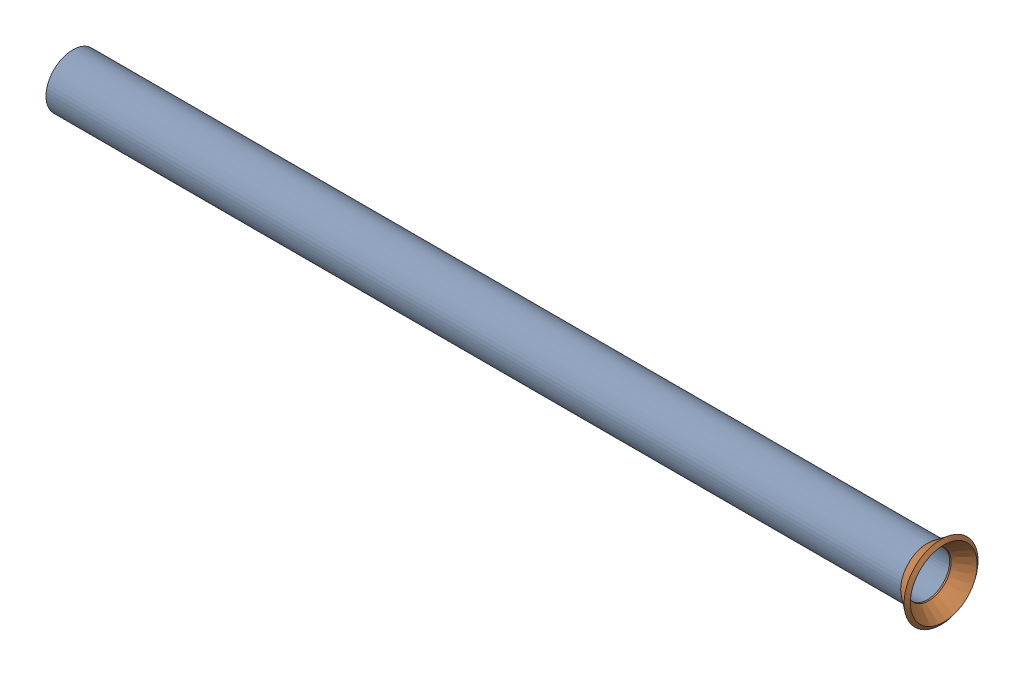
SolidWorks assembly Pipe 44, configuration Default. Lengths in mm.
Overall size (207.09 22.99 22.99).
2 component instances, 2 part files, 0 mates.
Components (placement in the parent):
- Part12-1: Part12 [Default<As Machined>] at (-618.6065 -1074.9029 485.9354) x (-1 0 0) z (0 0 -1) size (203.2 12.7 12.7)
- Flared pipe end - .5 inch-1: Flared pipe end - .5 inch [Default<As Machined>] at (-636.2287 452.6099 485.9354) x (0 0.383049 0.923728) z (1 0 0) size (17.59 17.59 3.89)
